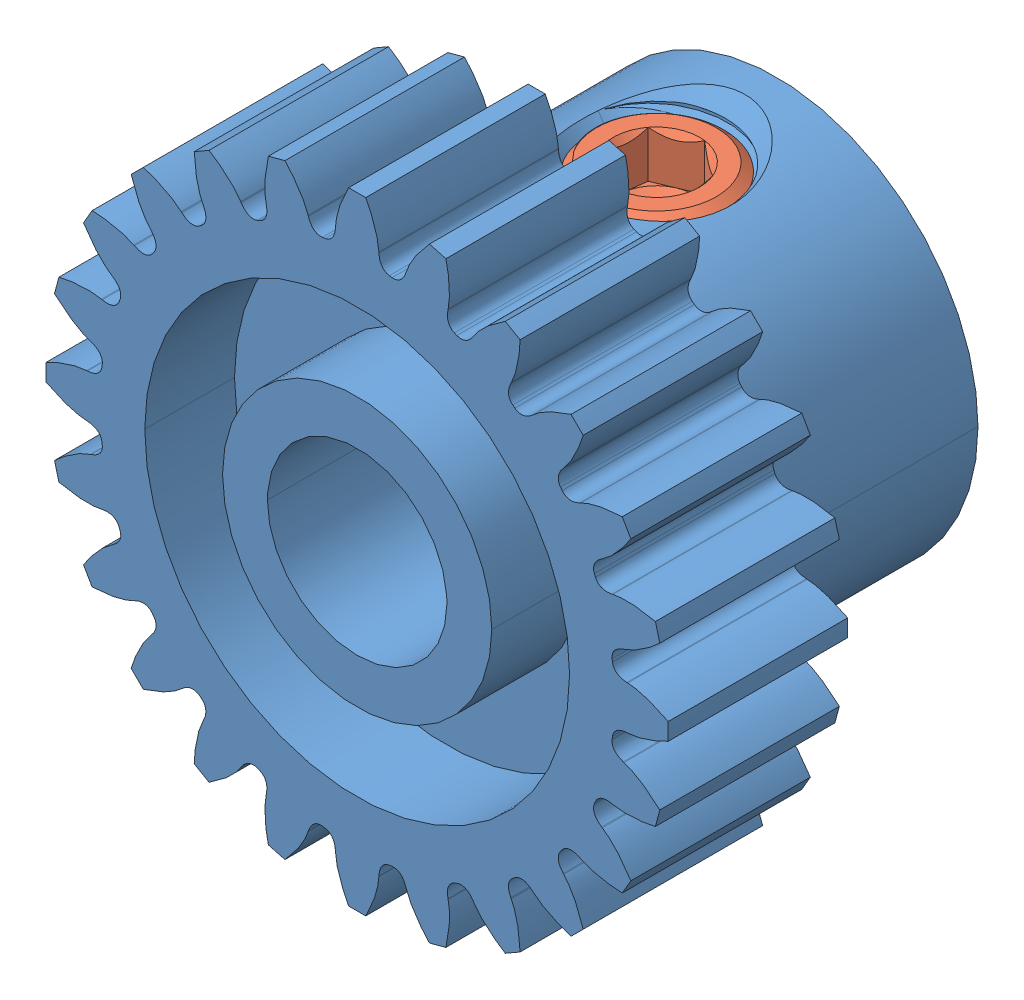
SolidWorks assembly 2304-0006-0024, configuration Default. Lengths in mm.
Overall size (20.8 20.8 14).
3 component instances, 2 part files, 0 mates.
Components (placement in the parent):
- 2304-0006-0024 assembly.STEP-1: 2304-0006-0024 assembly.STEP [Default] at origin size (20.8 20.8 14)
  - 2304-0006-0024_Gear Blank.STEP-1: 2304-0006-0024_Gear Blank.STEP [Default] at (-50.6401 18.8143 14.9399) size (20.8 20.8 14)
  - 2806-0004-0004_91390A117.STEP-1: 2806-0004-0004_91390A117.STEP [Default] at (-50.6401 23.5027 10.9399) x (0.991975 0 0.126432) z (0 1 0) size (5.01 5.01 4.01)
